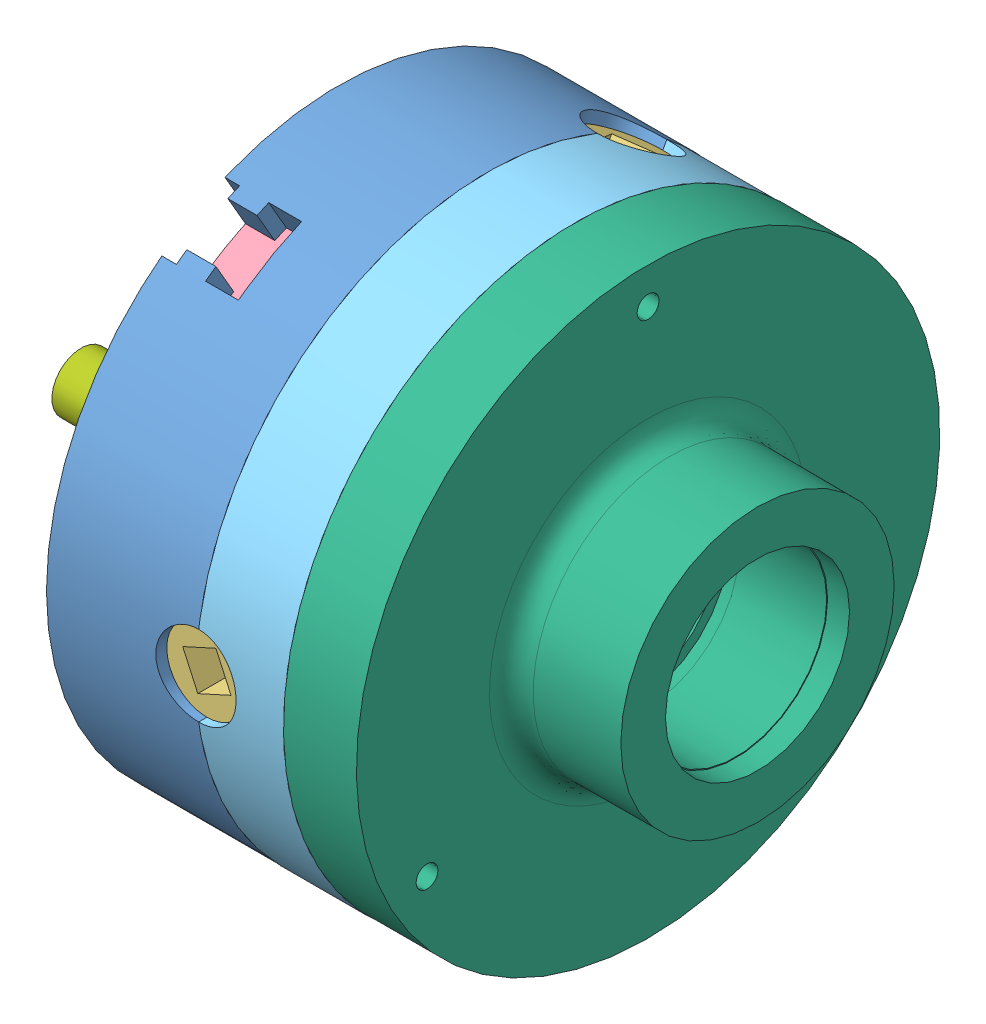
SolidWorks assembly SELF CENTERING CHUCK, configuration Default. Lengths in mm.
Overall size (135 218.56 218.56).
16 component instances, 8 part files, 17 mates.
Components (placement in the parent):
- FACE PLATE-1: FACE PLATE [Default] at (51.9599 86.5877 113.7606) size (41.88 160 160)
- scroll plate-1: scroll plate [Default] at (94.9599 86.5877 113.7606) x (0 -0.011206 0.999937) z (0 -0.999937 -0.011206) size (126.53 15.07 125)
- PINION-1: PINION [Default] at (92.9599 86.5877 134.7606) x (-0.91032 -0.413905 0) z (-0.413905 0.91032 0) size (46.94 76 24.38)
- JAW-2: JAW [Default] at (77.9599 86.2959 113.929) x (0 0.866025 -0.5) z (-1 0 0) size (60.01 20 50)
- JAW-3: JAW [Default] at (77.9599 86.8795 113.929) x (0 -0.866025 -0.5) z (-1 0 0) size (60.01 20 50)
- JAW-4: JAW [Default] at (77.9599 86.5877 113.4236) x (0 0 1) z (-1 0 0) size (60.01 20 50)
- PINION-2: PINION [Default] at (92.9599 104.7742 103.2606) x (-0.91032 0.206952 0.358452) z (-0.413905 -0.45516 -0.78836) size (46.94 76 24.38)
- PINION-3: PINION [Default] at (92.9599 68.4012 103.2606) x (-0.91032 0.206952 -0.358452) z (-0.413905 -0.45516 0.78836) size (46.94 76 24.38)
- BACK PLATE-1: BACK PLATE [Default] at (116.9599 86.5877 113.7606) x (1 0 0) z (0 0.5 0.866025) size (33 160 160)
- FLANGE-1: FLANGE [Default] at (113.9599 86.5877 113.7606) x (-1 0 0) z (0 0.866025 0.5) size (53 160 160)
- SOCKET SET SCREW 2-2: SOCKET SET SCREW 2 [Default] at (51.9599 16.7266 113.7606) x (0 1 0) z (0 0 1) size (16 80 16)
- SOCKET SET SCREW 2-3: SOCKET SET SCREW 2 [Default] at (51.9599 121.5182 174.262) x (0 -0.5 -0.866025) z (0 0.866025 -0.5) size (16 80 16)
- SOCKET SET SCREW 2-4: SOCKET SET SCREW 2 [Default] at (51.9599 121.5182 53.2591) x (0 -0.5 0.866025) z (0 -0.866025 -0.5) size (16 80 16)
- SOCKET SET SCREW 1-2: SOCKET SET SCREW 1 [Default] at (51.9599 96.5877 136.6734) x (0 0.968921 -0.247369) z (0 0.247369 0.968921) size (10 31 10)
- SOCKET SET SCREW 1-3: SOCKET SET SCREW 1 [Default] at (51.9599 101.4308 93.6439) x (0 -0.698689 -0.715426) z (0 0.715426 -0.698689) size (10 31 10)
- SOCKET SET SCREW 1-4: SOCKET SET SCREW 1 [Default] at (51.9599 61.7446 110.9644) x (0 -0.270232 0.962795) z (0 -0.962795 -0.270232) size (10 31 10)
Mates (geometry in assembly coordinates):
- Concentric1: concentric: cylinder of FACE PLATE-1 through (-948.0401 86.5877 113.7606) axis (-1 0 0) radius 30; cylinder of scroll plate-1 through (1094.9599 86.5877 113.7606) axis (1 0 0) radius 30
- Concentric2: concentric: cylinder of FACE PLATE-1 through (92.9599 86.5877 178.7606) axis (0 0 1) radius 11; cylinder of PINION-1 through (92.9599 86.5877 190.7606) axis (0 0 1) radius 11
- Coincident5: coincident: plane of FACE PLATE-1 through (92.9599 86.5877 178.7606) normal (0 0 -1); circle of PINION-1
- Coincident9: coincident: plane of FACE PLATE-1 through (55.9599 -11.3033 162.7724) normal (0 0.5 0.866025); plane of JAW-2 through (55.9599 73.8412 113.6142) normal (0 -0.5 -0.866025)
- RackPinionMate1: rack pinion = 0.3183 mm: line of JAW-2 through (63.9599 79.2384 129.5507) axis (0 -0.866025 0.5); circle of PINION-1
- Coincident10: coincident: plane of scroll plate-1 through (81.9599 72.4426 87.3046) normal (-1 0 0); plane of assembly through (81.9599 0 0) normal (1 0 0)
- Concentric3: concentric: cylinder of FACE PLATE-1 through (-948.0401 86.5877 113.7606) axis (-1 0 0) radius 20; cylinder of BACK PLATE-1 through (-883.0401 86.5877 113.7606) axis (-1 0 0) radius 20
- Concentric5: concentric: cylinder of BACK PLATE-1 through (-883.0401 86.5877 113.7606) axis (-1 0 0) radius 80; cylinder of FLANGE-1 through (1113.9599 86.5877 113.7606) axis (1 0 0) radius 80
- Coincident12: coincident: plane of BACK PLATE-1 through (113.9599 69.2672 123.7606) normal (1 0 0); plane of FLANGE-1 through (113.9599 56.5877 165.7221) normal (-1 0 0)
- Concentric10: concentric: cylinder of BACK PLATE-1 through (116.9599 51.5877 53.1388) axis (1 0 0) radius 3; cylinder of FLANGE-1 through (166.9599 51.5877 53.1388) axis (-1 0 0) radius 3
- Concentric11: concentric: cylinder of SOCKET SET SCREW 2-2 through (121.9599 16.7266 113.7606) axis (-1 0 0) radius 5; cylinder of FACE PLATE-1 through (92.9599 16.7266 113.7606) axis (-1 0 0) radius 5
- Coincident16: coincident: plane of FACE PLATE-1 through (51.9599 106.5877 113.7606) normal (-1 0 0); plane of SOCKET SET SCREW 2-2 through (51.9599 16.7266 113.7606) normal (1 0 0)
- Concentric12: concentric: cylinder of FACE PLATE-1 through (92.9609 96.5877 136.6734) axis (-1 0 0) radius 3; cylinder of SOCKET SET SCREW 1-2 through (76.9599 96.5877 136.6734) axis (-1 0 0) radius 3
- Coincident17: coincident: plane of FACE PLATE-1 through (51.9599 106.5877 113.7606) normal (-1 0 0); plane of SOCKET SET SCREW 1-2 through (51.9599 96.5877 136.6734) normal (1 0 0)
- Coincident18: coincident: plane of FACE PLATE-1 through (63.9599 -11.3033 162.7724) normal (1 0 0); plane of JAW-2 through (63.9599 73.8412 113.6142) normal (-1 0 0)
- Tangent1: tangent: cylinder of JAW-2 through (81.9599 71.8846 122.2494) axis (-1 0 0) radius 18; face of scroll plate-1
- Concentric13: concentric: cylinder of FACE PLATE-1 through (92.9599 142.8794 81.2606) axis (0 0.866025 -0.5) radius 11; cylinder of BACK PLATE-1 through (92.9599 17.3048 153.7611) axis (0 0.866025 -0.5) radius 11
